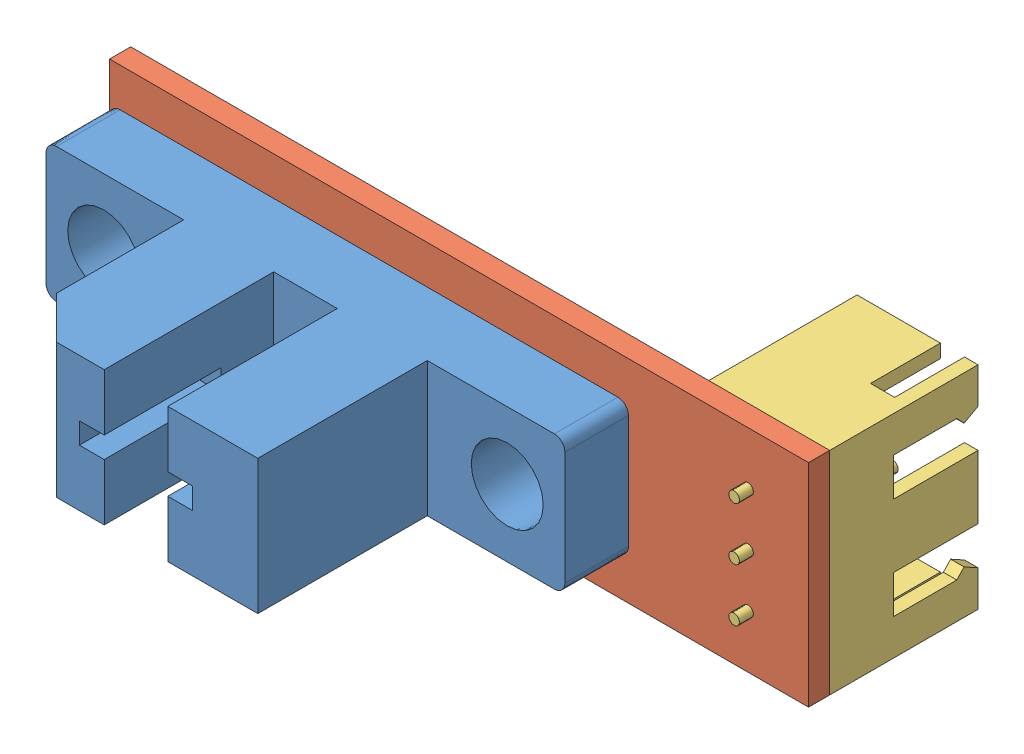
SolidWorks assembly Endstop_Opto_TCST2103 - Nov 2023, configuration Défaut. Lengths in mm.
Overall size (33 10 19).
3 component instances, 3 part files, 12 mates.
Components (placement in the parent):
- TCST2103^Endstop_Opto_TCST2103 - Nov 2023-1: TCST2103^Endstop_Opto_TCST2103 - Nov 2023 [Défaut] x (1 0 0) z (0 1 0) size (24.5 11 6.35) (virtual)
- PCB^Endstop_Opto_TCST2103 - Nov 2023-1: PCB^Endstop_Opto_TCST2103 - Nov 2023 [Défaut] x (1 0 0) z (0 0 -1) size (33 10 1) (virtual)
- Connector^Endstop_Opto_TCST2103 - Nov 2023-1: Connector^Endstop_Opto_TCST2103 - Nov 2023 [Défaut] at (0 0 -1) x (1 0 0) z (0 0 -1) size (5.71 10 8.66) (virtual)
Mates (geometry in assembly coordinates):
- Sur place1: in place: plane of TCST2103^Endstop_Opto_TCST2103 - Nov 2023-1 through (0 0 0) normal (0 1 0); moOrthogonalPlaneRef_w of TCST2103^Endstop_Opto_TCST2103 - Nov 2023-1 through (0 0 0) normal (0 0 -1); line of TCST2103^Endstop_Opto_TCST2103 - Nov 2023-1 through (55 -55 0) axis (0 0 1); unknown of TCST2103^Endstop_Opto_TCST2103 - Nov 2023-1
- Coïncidente1: coincident aligned: plane of assembly through (0 0 0) normal (0 1 0); plane of assembly through (0 0 0) normal (0 1 0)
- Coïncidente2: coincident aligned: plane of TCST2103^Endstop_Opto_TCST2103-1 through (0 0 0) normal (0 0 -1)
- Coïncidente3: coincident anti-aligned: plane of TCST2103^Endstop_Opto_TCST2103-1 through (0 0 0) normal (1 0 0)
- Sur place2: in place: plane of TCST2103^Endstop_Opto_TCST2103 - Nov 2023-1 through (-12.25 3.175 0) normal (0 0 -1); plane of ? through (0 0 0) normal (0 0 -1); plane of TCST2103^Endstop_Opto_TCST2103 - Nov 2023-1 through (-12.25 3.175 0) normal (0 0 -1); line of ? through (-55 0 0) axis (0 0 1); plane of TCST2103^Endstop_Opto_TCST2103 - Nov 2023-1 through (-12.25 3.175 0) normal (0 0 -1); plane of ? through (0 0 0) normal (-1 0 0); plane of TCST2103^Endstop_Opto_TCST2103 - Nov 2023-1 through (-12.25 3.175 0) normal (0 0 -1); unknown of PCB^Endstop_Opto_TCST2103 - Nov 2023-1
- Coïncidente4: coincident aligned: plane of ?; plane of ?
- Coïncidente5: coincident aligned: moOrthogonalPlaneRef_w of TCST2103^Endstop_Opto_TCST2103-1 through (0 0 0) normal (0 -1 0); plane of PCB^Endstop_Opto_TCST2103-1 through (0 0 0) normal (0 -1 0)
- Coïncidente6: coincident anti-aligned: moOrthogonalPlaneRef_w of TCST2103^Endstop_Opto_TCST2103-1 through (0 0 0) normal (-1 0 0); plane of PCB^Endstop_Opto_TCST2103-1 through (0 0 0) normal (1 0 0)
- Sur place3: in place: plane of PCB^Endstop_Opto_TCST2103 - Nov 2023-1 through (0 0 -1) normal (0 0 -1); plane of ? through (0 0 -1) normal (0 0 -1); plane of PCB^Endstop_Opto_TCST2103 - Nov 2023-1 through (0 0 -1) normal (0 0 -1); unknown of ?; plane of PCB^Endstop_Opto_TCST2103 - Nov 2023-1 through (0 0 -1) normal (0 0 -1); plane of ? through (0 0 -1) normal (-1 0 0); plane of PCB^Endstop_Opto_TCST2103 - Nov 2023-1 through (0 0 -1) normal (0 0 -1); unknown of Connector^Endstop_Opto_TCST2103 - Nov 2023-1
- Coïncidente7: coincident aligned: plane of ?; plane of ?
- Coïncidente8: coincident aligned: moOrthogonalPlaneRef_w of PCB^Endstop_Opto_TCST2103-1 through (0 0 -1) normal (0 -1 0); plane of Connector^Endstop_Opto_TCST2103-1 through (0 0 -1) normal (0 -1 0)
- Coïncidente9: coincident anti-aligned: moOrthogonalPlaneRef_w of PCB^Endstop_Opto_TCST2103-1 through (0 0 -1) normal (-1 0 0); plane of Connector^Endstop_Opto_TCST2103-1 through (0 0 -1) normal (1 0 0)
